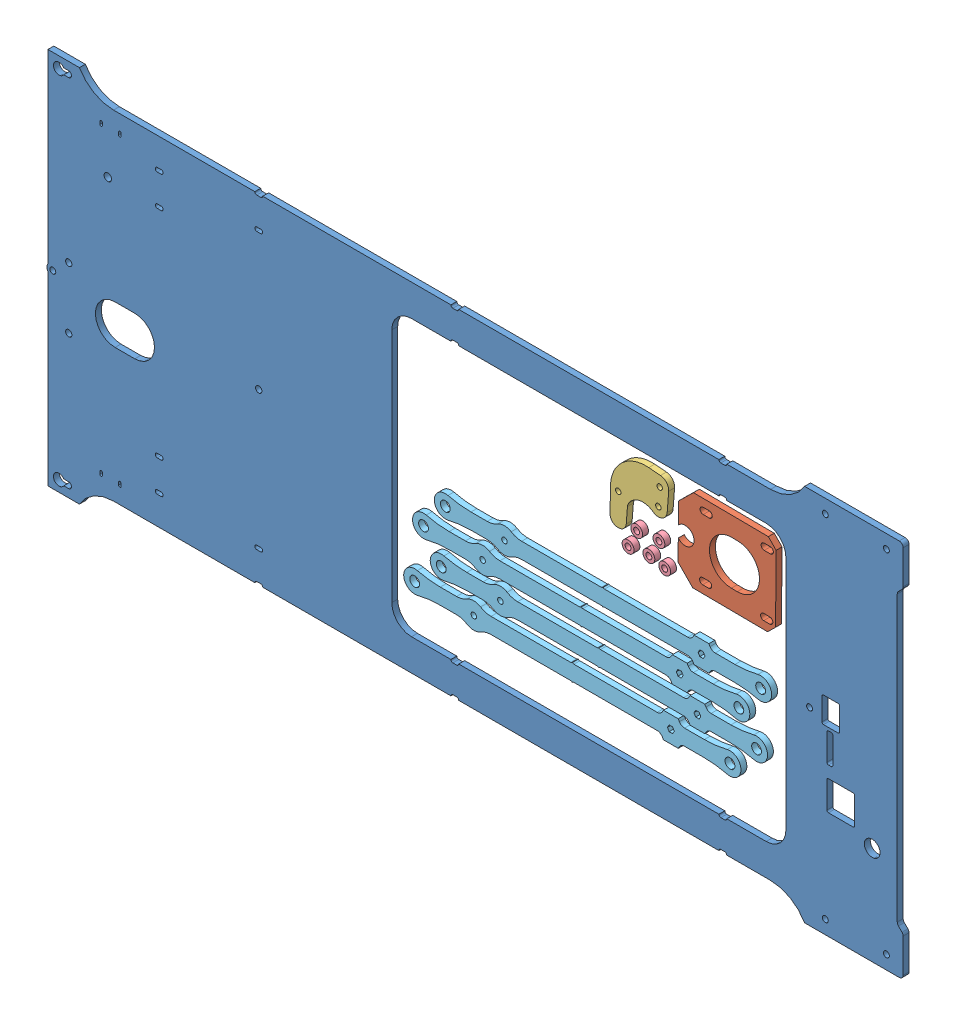
SolidWorks assembly 1196, configuration Default. Lengths in mm.
Overall size (450 200 7.5).
12 component instances, 5 part files, 10 mates.
Components (placement in the parent):
- 1303-2: 1303 [Default] at (402.2081 100.0698 0) x (0 1 0) z (0 0 1) size (191.84 434.5 3)
- 1307-8: 1307 [Default] at (356.11 143.8232 0) x (0.008727 0.999962 0) z (0 0 1) size (42 49.49 3)
- 1308-7: 1308 [Default] at (318.1838 158.9221 0) x (-0.996917 0.078459 0) z (0 0 1) size (28.5 35.3 3)
- 1298-1: 1298 [Default] at (317.7608 134.9479 0) size (6 6 3)
- 1298-2: 1298 [Default] at (303.614 126.1364 1.5) size (6 6 3)
- 1298-3: 1298 [Default] at (312.8309 125.9912 0.15) size (6 6 3)
- 1298-4: 1298 [Default] at (307.9822 135.2493 1.5) size (6 6 3)
- 1298-5: 1298 [Default] at (322.1908 125.8321 1.5) size (6 6 3)
- 1232-1: 1232 [Default] at (289.3875 96.0573 0) size (171.2 13 3)
- 1232-2: 1232 [Default] at (279.8259 83.4315 1.5) size (171.2 13 3)
- 1232-3: 1232 [Default] at (290.3082 71.4516 3) size (171.2 13 3)
- 1232-4: 1232 [Default] at (278.3284 59.7712 4.5) size (171.2 13 3)
Mates (geometry in assembly coordinates):
- Coincident1: coincident anti-aligned: plane of 1303-2 through (402.2081 100.0698 0) normal (0 0 -1); plane of assembly through (0 0 0) normal (0 0 1)
- Coincident2: coincident aligned: plane of 1303-2 through (402.2081 100.0698 0) normal (0 0 -1); plane of ? through (218.6537 68.3142 0) normal (0 0 -1)
- Coincident3: coincident aligned: plane of 1303-2 through (402.2081 100.0698 0) normal (0 0 -1); plane of ? through (265.9118 138.5803 0) normal (0 0 -1)
- Coincident4: coincident aligned: plane of 1303-2 through (402.2081 100.0698 0) normal (0 0 -1); plane of 1308-7 through (318.2465 159.7196 0) normal (0 0 -1)
- Coincident5: coincident aligned: plane of 1303-2 through (402.2081 100.0698 0) normal (0 0 -1); plane of ? through (355.2668 115.5957 0) normal (0 0 -1)
- Coincident6: coincident aligned: plane of 1303-2 through (402.2081 100.0698 0) normal (0 0 -1); plane of 1307-8 through (331.1109 144.0413 0) normal (0 0 -1)
- Coincident7: coincident aligned: plane of 1303-2 through (402.2081 100.0698 0) normal (0 0 -1); plane of ? through (199.4542 147.0694 0) normal (0 0 -1)
- Coincident8: coincident aligned: plane of 1303-2 through (402.2081 100.0698 0) normal (0 0 -1); plane of 1298-1 through (317.7608 134.9479 0) normal (0 0 -1)
- Coincident9: coincident aligned: plane of 1303-2 through (402.2081 100.0698 0) normal (0 0 -1); plane of ? through (265.9118 138.5803 0) normal (0 0 -1)
- Coincident10: coincident aligned: plane of 1303-2 through (402.2081 100.0698 0) normal (0 0 -1); plane of 1232-1 through (369.3875 96.0573 0) normal (0 0 -1)
